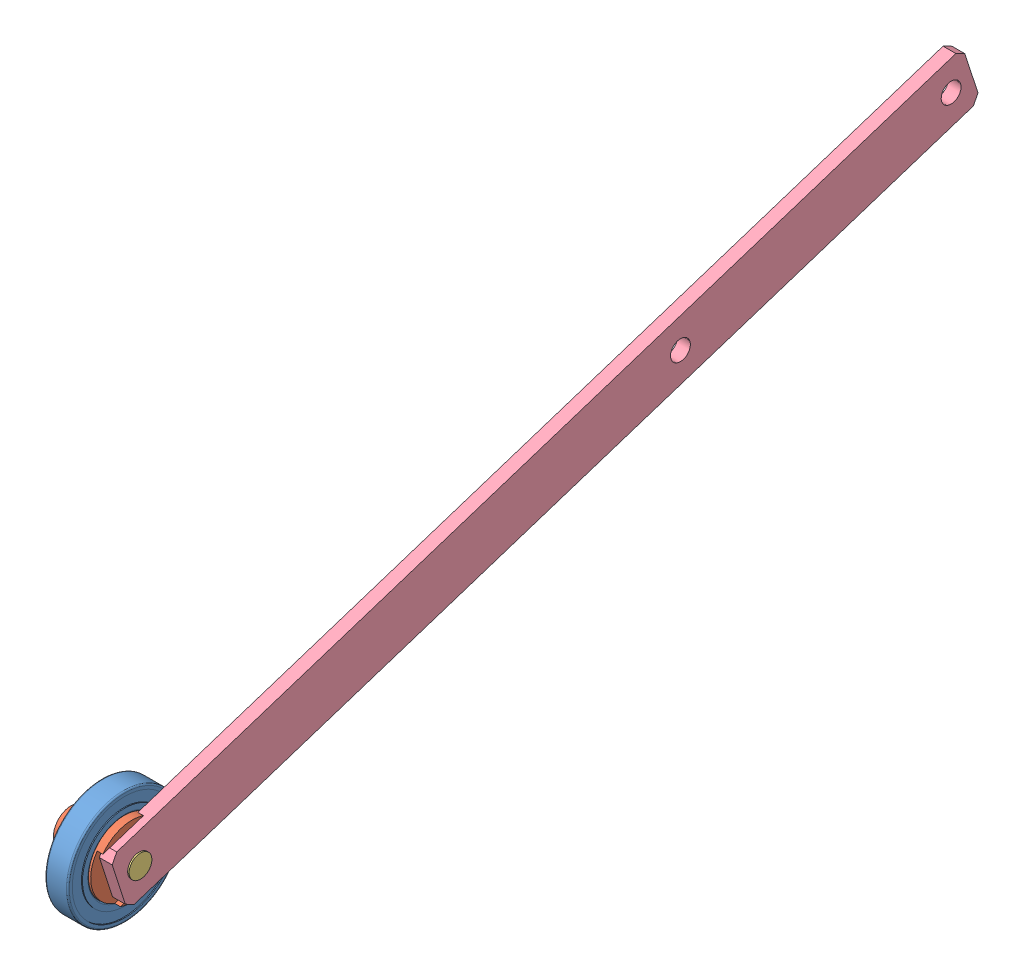
SolidWorks assembly 110303047-04, configuration 預設. Lengths in mm.
Overall size (48.7 258.53 641.16).
4 component instances, 4 part files, 6 mates.
Components (placement in the parent):
- 9-1: 9 [Default] at (-8.9411 29.2974 127.9169) x (1 0 0) z (0 -0.292163 0.956369) size (16 80 80)
- 110303047-08-1: 110303047-08 [預設] at (-8.9411 29.2974 127.9169) x (0 -0.951311 -0.308234) z (0 -0.308234 0.951311) size (57 42.7 57)
- 110303047-10-1: 110303047-10 [預設] at (4.0589 29.2974 127.9169) x (0 -0.428842 0.90338) z (0 0.90338 0.428842) size (16 14 16)
- 12-1: 12 [Default] at (8.0589 152.5908 -252.6074) x (0 0.308234 -0.951311) z (1 0 0) size (630 40 9)
Mates (geometry in assembly coordinates):
- 輪廓中心2: profile center aligned: plane of 110303047-08-1 through (-8.9411 4.4241 125.4031) normal (1 0 0); circle of 9-1
- 重合/共線/共點1: coincident anti-aligned: plane of 110303047-08-1 through (8.0589 39.5389 161.1939) normal (0 -0.951311 -0.308234); plane of 12-1 through (17.0589 45.2412 143.5947) normal (0 0.951311 0.308234)
- 同軸心1: concentric anti-aligned: cylinder of 110303047-10-1 through (22.0703 29.2974 127.9169) axis (1 0 0) radius 7; cylinder of 12-1 through (17.0589 29.2974 127.9169) axis (-1 0 0) radius 7
- 重合/共線/共點2: coincident anti-aligned: plane of 110303047-10-1 through (17.0589 25.8666 135.144) normal (-1 0 0); plane of 12-1 through (17.0589 152.5908 -252.6074) normal (1 0 0)
- 同軸心2: concentric aligned: cylinder of 110303047-08-1 through (4.0589 29.2974 127.9169) axis (1 0 0) radius 7; cylinder of 110303047-10-1 through (22.0703 29.2974 127.9169) axis (1 0 0) radius 7
- 重合/共線/共點3: coincident anti-aligned: plane of 110303047-08-1 through (8.0589 29.2974 127.9169) normal (1 0 0); plane of 12-1 through (8.0589 152.5908 -252.6074) normal (-1 0 0)
